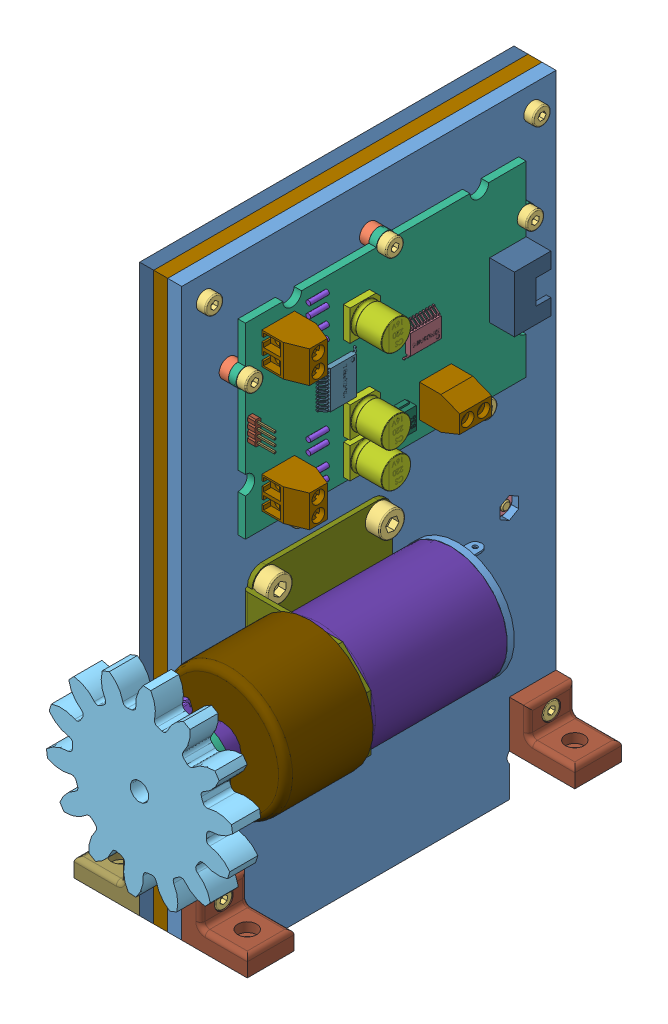
SolidWorks assembly moteur-complet, configuration Défaut. Lengths in mm.
Overall size (62.95 130 103.43).
90 component instances, 30 part files, 119 mates.
Components (placement in the parent):
- moteur-platine-1-4: moteur-platine-1 [Défaut] at (-59.9962 -68.9698 170) size (3 130 80)
- Grove button-1: Grove button [Défaut] at (-66.7015 -12.8903 110) x (0 -1 0) z (0 0 -1) size (20 11.6 23.6)
  - PCB grove 20x20-1: PCB grove 20x20 [Défaut] at (2.0795 1.2947 0) size (20 1.6 23.6)
  - 603 resistor 102-1: 603 resistor 102 [Default] at (2.0895 2.8947 -6.319) x (0 0 1) z (-1 0 0) size (2.36 0.62 1.03)
  - tactileswitch-CMS-1: tactileswitch-CMS [Default] at (-2.4169 2.8947 0.0035) x (0 0 1) z (-1 0 0) size (8.41 4.95 6.01)
  - Connecteur Grove (droit CMS)-1: Connecteur Grove (droit CMS) [Défaut] at (5.0795 2.8947 0) x (-1 0 0) z (0 1 0) size (6.5 14 10)
  - 603 resistor 102-2: 603 resistor 102 [Default] at (3.5895 2.8947 -6.319) x (0 0 1) z (-1 0 0) size (2.36 0.62 1.03)
- Grove I2C Motor driver TB6612FNG-1: Grove I2C Motor driver TB6612FNG [Défaut] at (-118.1962 28.5169 135.6463) x (0 0 1) z (1 0 0) size (64 44 12.2)
  - Plaque de base-1: Plaque de base [Défaut] at (-5.6463 -2.5133 63.2) size (64 44 1.6)
  - CS 220 16V-1: CS 220 16V [Défaut] at (0.1237 13.2167 64.8) x (1 0 0) z (0 -1 0) size (6.54 8.01 6.54)
  - CS 220 16V-2: CS 220 16V [Défaut] at (0.1237 5.6767 64.8) x (1 0 0) z (0 -1 0) size (6.54 8.01 6.54)
  - CS 220 16V-3: CS 220 16V [Défaut] at (0.1237 -12.2433 64.8) x (1 0 0) z (0 -1 0) size (6.54 8.01 6.54)
  - D1-1: D1 [Défaut] at (7.4081 5.2819 65.3) x (0 0.946795 -0.321836) z (1 0 0) size (1 1 4)
  - D1-2: D1 [Défaut] at (7.4081 7.7235 65.3) x (0 0.786026 0.618193) z (1 0 0) size (1 1 4)
  - D1-3: D1 [Défaut] at (7.4081 14.4025 65.3) x (0 0.953842 0.300308) z (1 0 0) size (1 1 4)
  - D1-4: D1 [Défaut] at (7.4081 11.9602 65.3) x (0 0.659384 0.751806) z (1 0 0) size (1 1 4)
  - D1-5: D1 [Défaut] at (7.4081 -17.5815 65.3) x (0 -0.999835 -0.018161) z (1 0 0) size (1 1 4)
  - D1-6: D1 [Défaut] at (7.4081 -14.133 65.3) x (0 0.806812 -0.590809) z (1 0 0) size (1 1 4)
  - D1-7: D1 [Défaut] at (7.4081 -11.4343 65.3) x (0 -0.166774 0.985995) z (1 0 0) size (1 1 4)
  - D1-8: D1 [Défaut] at (7.4081 -20.0356 65.3) x (0 0.962631 -0.270816) z (1 0 0) size (1 1 4)
  - bornier double-1: bornier double [Défaut] at (20.8537 7.1995 64.8) x (0 1 0) z (1 0 0) size (6.8 12.2 7)
  - bornier double-2: bornier double [Défaut] at (-12.8463 13.9867 64.8) x (-1 0 0) z (0 1 0) size (6.8 12.2 7)
  - bornier double-3: bornier double [Défaut] at (20.8537 -19.5133 64.8) x (0 1 0) z (1 0 0) size (6.8 12.2 7)
  - Grove Connecteur-1: Grove Connecteur [Défaut] at (-37.0963 -2.5133 64.05) x (1 0 0) z (0 -1 0) size (7.8 5.3 12)
  - Bloc 4 pins male-1: Bloc 4 pins male [Défaut] at (23.2493 -0.7812 63.276) x (0 -1 0) z (0 0 1) size (5.08 1.27 7.62)
    - Pin_cmi2c_Base-1: Pin_cmi2c_Base [Défaut] at (-0.1729 -0.0306 1.524) size (1.27 1.27 1.52)
    - Pin_cmi2c-1: Pin_cmi2c [Défaut] at (-0.1729 0.1472 -0.762) x (1 0 0) z (0 -1 0) size (0.36 7.62 0.36)
    - Pin_cmi2c-2: Pin_cmi2c [Défaut] at (1.0971 0.1472 -0.762) x (1 0 0) z (0 -1 0) size (0.36 7.62 0.36)
    - Pin_cmi2c-3: Pin_cmi2c [Défaut] at (2.3671 0.1472 -0.762) x (1 0 0) z (0 -1 0) size (0.36 7.62 0.36)
    - Pin_cmi2c-4: Pin_cmi2c [Défaut] at (3.6371 0.1472 -0.762) x (1 0 0) z (0 -1 0) size (0.36 7.62 0.36)
    - Pin_cmi2c_Base-2: Pin_cmi2c_Base [Défaut] at (1.0971 -0.0306 1.524) size (1.27 1.27 1.52)
    - Pin_cmi2c_Base-3: Pin_cmi2c_Base [Défaut] at (2.3671 -0.0306 1.524) size (1.27 1.27 1.52)
    - Pin_cmi2c_Base-4: Pin_cmi2c_Base [Défaut] at (3.6371 -0.0306 1.524) size (1.27 1.27 1.52)
  - Microcontroller 32F030F4P6-1: Microcontroller 32F030F4P6 [Défaut] at (-12.4961 -2.5519 65.5199) size (6.61 6.93 1.72)
  - Microcontroller TB6612FNG-1: Microcontroller TB6612FNG [Défaut] at (5.1421 -2.7086 65.5199) x (0 1 0) z (0 0 1) size (8 8.26 1.72)
  - PK13-1: PK13 [Défaut] at (-8.5328 11.2953 64.8) x (0 -1 0) z (-1 0 0) size (5.33 2 3.32)
- moteur MFA-1: moteur MFA [Défaut] at (-44.4916 -13.5198 141.6132) x (0 0 -1) z (0 -1 0) size (69.13 27.9 30)
  - moteur-support-1: moteur-support [Défaut] at (-14.3868 -12.5047 0) size (31 26.4 30)
  - moteur-corps-1: moteur-corps [Défaut] at (14.8132 1.8953 0) x (0 0 1) z (-1 0 0) size (24 24 62.63)
  - moteur-capuchon-1: moteur-capuchon [Défaut] at (-15.3868 1.8953 0) x (0 0 1) z (-1 0 0) size (27 27 18.7)
  - moteur-arriere-1: moteur-arriere [Défaut] at (16.3132 1.8953 0) x (0 0 1) z (-1 0 0) size (24 24 6.5)
- entretoise-grove-1: entretoise-grove [Défaut] at (-54.9962 51.0302 130) x (0 0.271539 0.962428) z (-1 0 0) size (4 4 2)
- entretoise-grove-2: entretoise-grove [Défaut] at (-54.9962 41.0302 100) x (0 0.358036 0.933708) z (-1 0 0) size (4 4 2)
- entretoise-grove-3: entretoise-grove [Défaut] at (-54.9962 41.0302 160) x (0 -0.42455 0.905404) z (-1 0 0) size (4 4 2)
- entretoise-grove-4: entretoise-grove [Défaut] at (-54.9962 11.0302 150) x (0 0 1) z (-1 0 0) size (4 4 2)
- entretoise-grove-5: entretoise-grove [Défaut] at (-54.9962 11.0302 110) x (0 0.014886 0.999889) z (-1 0 0) size (4 4 2)
- entretoise-grove-6: entretoise-grove [Défaut] at (-67.9962 -14.9698 120) x (0 0.014606 -0.999893) z (1 0 0) size (4 4 2)
- entretoise-grove-7: entretoise-grove [Défaut] at (-67.9962 -14.9698 100) x (0 0.432952 0.901417) z (1 0 0) size (4 4 2)
- vis-chc-1: vis-chc [Vis CHC M2x12] at (-69.5962 -14.9698 100) x (0 0.697993 -0.716105) z (0 0.716105 0.697993) size (3.8 14 3.8)
- vis-chc-2: vis-chc [Vis CHC M2x12] at (-69.5962 -14.9698 120) x (0 0.185382 -0.982666) z (0 0.982666 0.185382) size (3.8 14 3.8)
- vis-chc-3: vis-chc [Vis CHC M2x12] at (-53.3962 41.0302 100) x (0 0.381849 -0.924225) z (0 -0.924225 -0.381849) size (3.8 14 3.8)
- vis-chc-4: vis-chc [Vis CHC M2x12] at (-53.3962 51.0302 130) x (0 0.381849 -0.924225) z (0 -0.924225 -0.381849) size (3.8 14 3.8)
- vis-chc-5: vis-chc [Vis CHC M2x12] at (-53.3962 41.0302 160) x (0 0.381849 -0.924225) z (0 -0.924225 -0.381849) size (3.8 14 3.8)
- vis-chc-6: vis-chc [Vis CHC M2x12] at (-53.3962 11.0302 150) x (0 0.381849 -0.924225) z (0 -0.924225 -0.381849) size (3.8 14 3.8)
- vis-chc-7: vis-chc [Vis CHC M2x12] at (-53.3962 11.0302 110) x (0 0.381849 -0.924225) z (0 -0.924225 -0.381849) size (3.8 14 3.8)
- ecrou-h-2: ecrou-h [6007 HU M2] at (-59.9962 -14.9698 120) x (0 0.866025 0.5) z (0 -0.5 0.866025) size (4 1.6 4.62)
- ecrou-h-3: ecrou-h [6007 HU M2] at (-59.9962 -14.9698 100) x (0 0 1) z (0 -1 0) size (4 1.6 4.62)
- ecrou-h-4: ecrou-h [6007 HU M2] at (-64.5962 11.0302 110) x (0 0.866025 0.5) z (0 -0.5 0.866025) size (4 1.6 4.62)
- ecrou-h-5: ecrou-h [6007 HU M2] at (-64.5962 11.0302 150) x (0 0.866025 0.5) z (0 -0.5 0.866025) size (4 1.6 4.62)
- ecrou-h-6: ecrou-h [6007 HU M2] at (-64.5962 41.0302 160) x (0 0.866025 0.5) z (0 -0.5 0.866025) size (4 1.6 4.62)
- ecrou-h-7: ecrou-h [6007 HU M2] at (-64.5962 51.0302 130) x (0 0.866025 0.5) z (0 -0.5 0.866025) size (4 1.6 4.62)
- ecrou-h-8: ecrou-h [6007 HU M2] at (-64.5962 41.0302 100) x (0 0.866025 0.5) z (0 -0.5 0.866025) size (4 1.6 4.62)
- vis-chc-8: vis-chc [Vis CHC M3x10] at (-55.9962 -1.5198 129) x (0 0.773717 -0.633531) z (0 -0.633531 -0.773717) size (5.5 13 5.5)
- vis-chc-9: vis-chc [Vis CHC M3x10] at (-55.9962 -1.5198 153) x (0 0.483049 -0.875594) z (0 -0.875594 -0.483049) size (5.5 13 5.5)
- vis-chc-10: vis-chc [Vis CHC M3x10] at (-55.9962 -25.5198 153) x (0 0.381849 -0.924225) z (0 -0.924225 -0.381849) size (5.5 13 5.5)
- vis-chc-11: vis-chc [Vis CHC M3x10] at (-55.9962 -25.5198 129) x (0 0.381849 -0.924225) z (0 -0.924225 -0.381849) size (5.5 13 5.5)
- ecrou-h-9: ecrou-h [6012 HU M3] at (-65.3962 -1.5198 153) x (0 0.866025 0.5) z (0 -0.5 0.866025) size (5.5 2.4 6.35)
- ecrou-h-10: ecrou-h [6012 HU M3] at (-65.3962 -25.5198 153) x (0 0.866025 0.5) z (0 -0.5 0.866025) size (5.5 2.4 6.35)
- ecrou-h-11: ecrou-h [6012 HU M3] at (-65.3962 -25.5198 129) x (0 0.866025 -0.5) z (0 0.5 0.866025) size (5.5 2.4 6.35)
- ecrou-h-12: ecrou-h [6012 HU M3] at (-65.3962 -1.5198 129) x (0 0.866025 -0.5) z (0 0.5 0.866025) size (5.5 2.4 6.35)
- vis-chc-12: vis-chc [Vis CHC M2x12] at (-56.9962 56.0302 165) x (0 0.381849 -0.924225) z (0 -0.924225 -0.381849) size (3.8 14 3.8)
- vis-chc-13: vis-chc [Vis CHC M2x12] at (-56.9962 56.0302 95) x (0 -0.857895 -0.513826) z (0 -0.513826 0.857895) size (3.8 14 3.8)
- vis-chc-14: vis-chc [Vis CHC M2x16] at (-54.9962 -52.9698 95) x (0 -0.431797 -0.901971) z (0 -0.901971 0.431797) size (3.8 18 3.8)
- vis-chc-15: vis-chc [Vis CHC M2x16] at (-54.9962 -52.9698 165) x (0 0.381849 -0.924225) z (0 -0.924225 -0.381849) size (3.8 18 3.8)
- ecrou-h-13: ecrou-h [6007 HU M2] at (-67.5962 56.0302 165) x (0 0.866025 0.5) z (0 -0.5 0.866025) size (4 1.6 4.62)
- ecrou-h-14: ecrou-h [6007 HU M2] at (-67.5962 56.0302 95) x (0 0.866025 0.5) z (0 -0.5 0.866025) size (4 1.6 4.62)
- ecrou-h-15: ecrou-h [6007 HU M2] at (-69.5962 -52.9698 165) x (0 1 0) z (0 0 1) size (4 1.6 4.62)
- ecrou-h-16: ecrou-h [6007 HU M2] at (-69.5962 -52.9698 95) x (0 0.5 0.866025) z (0 -0.866025 0.5) size (4 1.6 4.62)
- engrenage-complet-1: engrenage-complet [Défaut] at (-42.1676 -13.7474 193.43) x (0.932852 0.36026 0) z (0 0 -1) size (39.32 40 14.36)
  - engrenage-1: engrenage [Défaut] at (1.0609 0.1936 0) size (39.32 40 6)
  - engrenage-bague_arret-1: engrenage-bague_arret [Défaut] at (-0.3178 -0.3667 13.5) x (-1 0 0) z (0 0 -1) size (24 24 8)
  - vis-tc-m3x6.5-1: vis-tc-m3x6.5 [Défaut] at (8.6822 -0.3667 1.1) x (1 0 0) z (0 -1 0) size (5.6 8.09 5.6)
  - vis-tc-m3x6.5-2: vis-tc-m3x6.5 [Défaut] at (-9.3178 -0.3667 1.1) x (1 0 0) z (0 -1 0) size (5.6 8.09 5.6)
  - vis-tc-m3x6-1: vis-tc-m3x6 [Défaut] at (-0.3178 -8.4167 10.5) x (-0.611546 0 0.791209) z (0.791209 0 0.611546) size (5.5 7.83 5.5)
- moteur-platine-2-5: moteur-platine-2 [Défaut] at (-62.9962 -68.9698 170) size (3 130 80)
- moteur-platine-3-3: moteur-platine-3 [Défaut] at (-65.9962 -68.9698 170) size (3 130 80)
- equerre-1: equerre [Défaut] at (-56.9962 -59.9698 165) x (0 0 -1) z (1 0 0) size (10 10 14)
- equerre-2: equerre [Défaut] at (-56.9962 -59.9698 95) x (0 0 -1) z (1 0 0) size (10 10 14)
- equerre-ecrou-1: equerre-ecrou [Défaut] at (-65.9962 -59.9698 95) x (0 0 1) z (-1 0 0) size (10 10 14)
- equerre-ecrou-2: equerre-ecrou [Défaut] at (-65.9962 -59.9698 165) x (0 0 1) z (-1 0 0) size (10 10 14)
Mates (geometry in assembly coordinates):
- Coïncidente1: coincident anti-aligned: plane of moteur-platine-1 through (-56.9962 -61.1012 161.1314) normal (1 0 0); plane of moteur MFA-1/moteur-support-1 through (-56.9962 -25.5198 153) normal (-1 0 0)
- Coaxiale1: concentric anti-aligned: cylinder of moteur-platine-1 through (-59.9962 -1.5198 129) axis (1 0 0) radius 1.5; cylinder of moteur MFA-1/moteur-support-1 through (-30.5962 -1.5198 129) axis (-1 0 0) radius 1.65
- Coaxiale2: concentric anti-aligned: cylinder of moteur-platine-1 through (-59.9962 -25.5198 129) axis (1 0 0) radius 1.5; cylinder of moteur MFA-1/moteur-support-1 through (-30.5962 -25.5198 129) axis (-1 0 0) radius 1.65
- Parallèle1: parallel aligned: plane of moteur-platine-1 through (-56.9962 61.0302 90) normal (0 0 -1); plane of Grove I2C Motor driver TB6612FNG-1/Plaque de base-1 through (-53.3962 11.0302 100) normal (0 0 -1)
- Parallèle2: parallel aligned: plane of moteur-platine-1 through (-56.9962 61.0302 170) normal (0 1 0); plane of Grove I2C Motor driver TB6612FNG-1/Plaque de base-1 through (-53.3962 51.0302 132) normal (0 1 0)
- Coaxiale3: concentric anti-aligned: cylinder of Grove I2C Motor driver TB6612FNG-1/Plaque de base-1 through (-53.3962 11.0302 110) axis (-1 0 0) radius 1; cylinder of entretoise-grove-5 through (-56.9962 11.0302 110) axis (1 0 0) radius 1
- Coïncidente4: coincident anti-aligned: plane of Grove I2C Motor driver TB6612FNG-1/Plaque de base-1 through (-54.9962 21.0302 100) normal (-1 0 0); plane of entretoise-grove-5 through (-54.9962 11.0302 110) normal (1 0 0)
- Coaxiale4: concentric anti-aligned: cylinder of Grove I2C Motor driver TB6612FNG-1/Plaque de base-1 through (-53.3962 11.0302 150) axis (-1 0 0) radius 1; cylinder of entretoise-grove-4 through (-56.9962 11.0302 150) axis (1 0 0) radius 1
- Coïncidente5: coincident anti-aligned: plane of Grove I2C Motor driver TB6612FNG-1/Plaque de base-1 through (-54.9962 21.0302 100) normal (-1 0 0); plane of entretoise-grove-4 through (-54.9962 11.0302 150) normal (1 0 0)
- Coaxiale5: concentric anti-aligned: cylinder of Grove I2C Motor driver TB6612FNG-1/Plaque de base-1 through (-53.3962 41.0302 100) axis (-1 0 0) radius 1; cylinder of entretoise-grove-2 through (-56.9962 41.0302 100) axis (1 0 0) radius 1
- Coïncidente6: coincident anti-aligned: plane of Grove I2C Motor driver TB6612FNG-1/Plaque de base-1 through (-54.9962 21.0302 100) normal (-1 0 0); plane of entretoise-grove-2 through (-54.9962 41.0302 100) normal (1 0 0)
- Coaxiale6: concentric anti-aligned: cylinder of Grove I2C Motor driver TB6612FNG-1/Plaque de base-1 through (-53.3962 41.0302 160) axis (-1 0 0) radius 1; cylinder of entretoise-grove-3 through (-56.9962 41.0302 160) axis (1 0 0) radius 1
- Coïncidente7: coincident anti-aligned: plane of Grove I2C Motor driver TB6612FNG-1/Plaque de base-1 through (-54.9962 21.0302 100) normal (-1 0 0); plane of entretoise-grove-3 through (-54.9962 41.0302 160) normal (1 0 0)
- Coaxiale7: concentric anti-aligned: cylinder of Grove I2C Motor driver TB6612FNG-1/Plaque de base-1 through (-53.3962 51.0302 130) axis (-1 0 0) radius 1; cylinder of entretoise-grove-1 through (-56.9962 51.0302 130) axis (1 0 0) radius 1
- Coïncidente8: coincident anti-aligned: plane of Grove I2C Motor driver TB6612FNG-1/Plaque de base-1 through (-54.9962 21.0302 100) normal (-1 0 0); plane of entretoise-grove-1 through (-54.9962 51.0302 130) normal (1 0 0)
- Coïncidente9: coincident anti-aligned: plane of moteur-platine-1 through (-56.9962 -61.1012 161.1314) normal (1 0 0); plane of entretoise-grove-3 through (-56.9962 41.0302 160) normal (-1 0 0)
- Coaxiale8: concentric aligned: cylinder of moteur-platine-1 through (-59.9962 11.0302 150) axis (1 0 0) radius 1; cylinder of entretoise-grove-4 through (-56.9962 11.0302 150) axis (1 0 0) radius 1
- Coaxiale9: concentric anti-aligned: cylinder of Grove button-1/PCB grove 20x20-1 through (-69.5962 -14.9698 120) axis (1 0 0) radius 1.1; cylinder of entretoise-grove-6 through (-65.9962 -14.9698 120) axis (-1 0 0) radius 1
- Coaxiale10: concentric anti-aligned: cylinder of Grove button-1/PCB grove 20x20-1 through (-69.5962 -14.9698 100) axis (1 0 0) radius 1.1; cylinder of entretoise-grove-7 through (-65.9962 -14.9698 100) axis (-1 0 0) radius 1
- Coïncidente11: coincident anti-aligned: plane of Grove button-1/PCB grove 20x20-1 through (-67.9962 -14.9698 110) normal (1 0 0); plane of entretoise-grove-7 through (-67.9962 -14.9698 100) normal (-1 0 0)
- Coaxiale13: concentric anti-aligned: cylinder of moteur MFA-1/moteur-corps-1 through (-42.5962 -13.5198 189.43) axis (0 0 -1) radius 2; cylinder of engrenage-complet-1/engrenage-bague_arret-1 through (-42.5962 -13.5198 179.93) axis (0 0 1) radius 2.05
- Distance1: distance = 0.5 mm anti-aligned: plane of engrenage-complet-1/engrenage-bague_arret-1 through (-42.5962 -13.5198 179.93) normal (0 0 -1); plane of moteur MFA-1/moteur-corps-1 through (-42.5962 -13.5198 179.43) normal (0 0 1)
- Coïncidente12: coincident anti-aligned: plane of moteur-platine-1 through (-59.9962 -61.1012 161.1314) normal (-1 0 0); plane of moteur-platine-2 through (-59.9962 -61.1012 161.1314) normal (1 0 0)
- Coïncidente13: coincident aligned: plane of moteur-platine-1 through (-56.9962 61.0302 170) normal (0 1 0); plane of moteur-platine-2 through (-59.9962 61.0302 170) normal (0 1 0)
- Coïncidente14: coincident aligned: plane of moteur-platine-1 through (-56.9962 61.0302 90) normal (0 0 -1); plane of moteur-platine-2 through (-59.9962 61.0302 90) normal (0 0 -1)
- Coïncidente15: coincident anti-aligned: plane of moteur-platine-2 through (-62.9962 -61.1012 161.1314) normal (-1 0 0); plane of moteur-platine-3-3 through (-62.9962 -61.1012 161.1314) normal (1 0 0)
- Coïncidente16: coincident aligned: plane of moteur-platine-2 through (-59.9962 61.0302 170) normal (0 1 0); plane of moteur-platine-3-3 through (-62.9962 61.0302 170) normal (0 1 0)
- Coïncidente17: coincident aligned: plane of moteur-platine-1 through (-56.9962 61.0302 90) normal (0 0 -1); plane of moteur-platine-3-3 through (-62.9962 61.0302 90) normal (0 0 -1)
- Coïncidente18: coincident anti-aligned: plane of entretoise-grove-7 through (-65.9962 -14.9698 100) normal (1 0 0); plane of moteur-platine-3-3 through (-65.9962 -61.1012 161.1314) normal (-1 0 0)
- Coïncidente19: coincident anti-aligned: plane of entretoise-grove-6 through (-65.9962 -14.9698 120) normal (1 0 0); plane of moteur-platine-3-3 through (-65.9962 -61.1012 161.1314) normal (-1 0 0)
- Coïncidente21: coincident anti-aligned: plane of Grove button-1/PCB grove 20x20-1 through (-69.5962 -14.9698 110) normal (-1 0 0); plane of vis-chc-2 through (-69.5962 -14.9698 120) normal (1 0 0)
- Coaxiale15: concentric aligned: cylinder of vis-chc-2 through (-57.5962 -14.9698 120) axis (-1 0 0) radius 1; cylinder of ecrou-h-2 through (-58.3962 -14.9698 120) axis (-1 0 0) radius 0.7835
- Parallèle4: parallel aligned: plane of moteur-platine-1 through (-56.9962 61.0302 90) normal (0 0 -1); plane of ecrou-h-2 through (-58.3962 -13.8151 118) normal (0 0 -1)
- Coïncidente25: coincident anti-aligned: plane of Grove button-1/PCB grove 20x20-1 through (-69.5962 -14.9698 110) normal (-1 0 0); plane of vis-chc-1 through (-69.5962 -14.9698 100) normal (1 0 0)
- Coaxiale17: concentric aligned: cylinder of vis-chc-1 through (-57.5962 -14.9698 100) axis (-1 0 0) radius 1; cylinder of ecrou-h-3 through (-58.3962 -14.9698 100) axis (-1 0 0) radius 0.7835
- Parallèle5: parallel aligned: plane of moteur-platine-1 through (-56.9962 61.0302 90) normal (0 0 -1); plane of ecrou-h-3 through (-58.3962 -13.8151 98) normal (0 0 -1)
- Coaxiale18: concentric anti-aligned: cylinder of Grove I2C Motor driver TB6612FNG-1/Plaque de base-1 through (-53.3962 11.0302 110) axis (-1 0 0) radius 1; cylinder of vis-chc-7 through (-65.3962 11.0302 110) axis (1 0 0) radius 1
- Coaxiale19: concentric anti-aligned: cylinder of Grove I2C Motor driver TB6612FNG-1/Plaque de base-1 through (-53.3962 11.0302 150) axis (-1 0 0) radius 1; cylinder of vis-chc-6 through (-65.3962 11.0302 150) axis (1 0 0) radius 1
- Coaxiale20: concentric anti-aligned: cylinder of Grove I2C Motor driver TB6612FNG-1/Plaque de base-1 through (-53.3962 41.0302 160) axis (-1 0 0) radius 1; cylinder of vis-chc-5 through (-65.3962 41.0302 160) axis (1 0 0) radius 1
- Coaxiale21: concentric anti-aligned: cylinder of Grove I2C Motor driver TB6612FNG-1/Plaque de base-1 through (-53.3962 51.0302 130) axis (-1 0 0) radius 1; cylinder of vis-chc-4 through (-65.3962 51.0302 130) axis (1 0 0) radius 1
- Coaxiale22: concentric anti-aligned: cylinder of Grove I2C Motor driver TB6612FNG-1/Plaque de base-1 through (-53.3962 41.0302 100) axis (-1 0 0) radius 1; cylinder of vis-chc-3 through (-65.3962 41.0302 100) axis (1 0 0) radius 1
- Coïncidente28: coincident anti-aligned: plane of Grove I2C Motor driver TB6612FNG-1/Plaque de base-1 through (-53.3962 21.0302 100) normal (1 0 0); plane of vis-chc-3 through (-53.3962 41.0302 100) normal (-1 0 0)
- Coïncidente29: coincident anti-aligned: plane of Grove I2C Motor driver TB6612FNG-1/Plaque de base-1 through (-53.3962 21.0302 100) normal (1 0 0); plane of vis-chc-4 through (-53.3962 51.0302 130) normal (-1 0 0)
- Coïncidente30: coincident anti-aligned: plane of Grove I2C Motor driver TB6612FNG-1/Plaque de base-1 through (-53.3962 21.0302 100) normal (1 0 0); plane of vis-chc-5 through (-53.3962 41.0302 160) normal (-1 0 0)
- Coïncidente31: coincident anti-aligned: plane of Grove I2C Motor driver TB6612FNG-1/Plaque de base-1 through (-53.3962 21.0302 100) normal (1 0 0); plane of vis-chc-6 through (-53.3962 11.0302 150) normal (-1 0 0)
- Coïncidente32: coincident anti-aligned: plane of Grove I2C Motor driver TB6612FNG-1/Plaque de base-1 through (-53.3962 21.0302 100) normal (1 0 0); plane of vis-chc-7 through (-53.3962 11.0302 110) normal (-1 0 0)
- Coaxiale23: concentric anti-aligned: cylinder of vis-chc-7 through (-65.3962 11.0302 110) axis (1 0 0) radius 1; cylinder of ecrou-h-4 through (-62.9962 11.0302 110) axis (-1 0 0) radius 0.7835
- Coaxiale24: concentric anti-aligned: cylinder of vis-chc-3 through (-65.3962 41.0302 100) axis (1 0 0) radius 1; cylinder of ecrou-h-8 through (-62.9962 41.0302 100) axis (-1 0 0) radius 0.7835
- Coaxiale25: concentric anti-aligned: cylinder of vis-chc-4 through (-65.3962 51.0302 130) axis (1 0 0) radius 1; cylinder of ecrou-h-7 through (-62.9962 51.0302 130) axis (-1 0 0) radius 0.7835
- Coaxiale26: concentric anti-aligned: cylinder of vis-chc-5 through (-65.3962 41.0302 160) axis (1 0 0) radius 1; cylinder of ecrou-h-6 through (-62.9962 41.0302 160) axis (-1 0 0) radius 0.7835
- Coaxiale27: concentric anti-aligned: cylinder of vis-chc-6 through (-65.3962 11.0302 150) axis (1 0 0) radius 1; cylinder of ecrou-h-5 through (-62.9962 11.0302 150) axis (-1 0 0) radius 0.7835
- Parallèle6: parallel aligned: plane of moteur-platine-3-3 through (-62.9962 -59.9698 170) normal (0 0 1); plane of ecrou-h-6 through (-62.9962 39.8755 162) normal (0 0 1)
- Parallèle7: parallel aligned: plane of moteur-platine-3-3 through (-62.9962 -59.9698 170) normal (0 0 1); plane of ecrou-h-7 through (-62.9962 49.8755 132) normal (0 0 1)
- Parallèle8: parallel aligned: plane of moteur-platine-3-3 through (-62.9962 -59.9698 170) normal (0 0 1); plane of ecrou-h-8 through (-62.9962 39.8755 102) normal (0 0 1)
- Parallèle9: parallel aligned: plane of moteur-platine-3-3 through (-62.9962 -59.9698 170) normal (0 0 1); plane of ecrou-h-5 through (-62.9962 9.8755 152) normal (0 0 1)
- Parallèle10: parallel aligned: plane of moteur-platine-3-3 through (-62.9962 -59.9698 170) normal (0 0 1); plane of ecrou-h-4 through (-62.9962 9.8755 112) normal (0 0 1)
- Coaxiale28: concentric anti-aligned: cylinder of moteur MFA-1/moteur-support-1 through (-30.5962 -1.5198 153) axis (-1 0 0) radius 1.65; cylinder of vis-chc-9 through (-65.9962 -1.5198 153) axis (1 0 0) radius 1.5
- Coaxiale29: concentric anti-aligned: cylinder of moteur MFA-1/moteur-support-1 through (-30.5962 -1.5198 129) axis (-1 0 0) radius 1.65; cylinder of vis-chc-8 through (-65.9962 -1.5198 129) axis (1 0 0) radius 1.5
- Coaxiale30: concentric anti-aligned: cylinder of moteur MFA-1/moteur-support-1 through (-30.5962 -25.5198 129) axis (-1 0 0) radius 1.65; cylinder of vis-chc-11 through (-65.9962 -25.5198 129) axis (1 0 0) radius 1.5
- Coaxiale31: concentric anti-aligned: cylinder of moteur MFA-1/moteur-support-1 through (-30.5962 -25.5198 153) axis (-1 0 0) radius 1.65; cylinder of vis-chc-10 through (-65.9962 -25.5198 153) axis (1 0 0) radius 1.5
- Coïncidente43: coincident anti-aligned: plane of moteur MFA-1/moteur-support-1 through (-55.9962 -29.752 156) normal (1 0 0); plane of vis-chc-11 through (-55.9962 -25.5198 129) normal (-1 0 0)
- Coïncidente44: coincident aligned: plane of moteur MFA-1/moteur-support-1 through (-55.9962 -29.752 156) normal (1 0 0); circle of vis-chc-10
- Coïncidente45: coincident anti-aligned: plane of moteur MFA-1/moteur-support-1 through (-55.9962 -29.752 156) normal (1 0 0); plane of vis-chc-8 through (-55.9962 -1.5198 129) normal (-1 0 0)
- Coïncidente46: coincident anti-aligned: plane of moteur MFA-1/moteur-support-1 through (-55.9962 -29.752 156) normal (1 0 0); plane of vis-chc-9 through (-55.9962 -1.5198 153) normal (-1 0 0)
- Coaxiale32: concentric anti-aligned: cylinder of vis-chc-8 through (-65.9962 -1.5198 129) axis (1 0 0) radius 1.5; cylinder of ecrou-h-12 through (-62.9962 -1.5198 129) axis (-1 0 0) radius 1.2295
- Coaxiale33: concentric anti-aligned: cylinder of vis-chc-10 through (-65.9962 -25.5198 153) axis (1 0 0) radius 1.5; cylinder of ecrou-h-10 through (-62.9962 -25.5198 153) axis (-1 0 0) radius 1.2295
- Coaxiale34: concentric anti-aligned: cylinder of vis-chc-9 through (-65.9962 -1.5198 153) axis (1 0 0) radius 1.5; cylinder of ecrou-h-9 through (-62.9962 -1.5198 153) axis (-1 0 0) radius 1.2295
- Coaxiale35: concentric anti-aligned: cylinder of vis-chc-11 through (-65.9962 -25.5198 129) axis (1 0 0) radius 1.5; cylinder of ecrou-h-11 through (-62.9962 -25.5198 129) axis (-1 0 0) radius 1.2295
- Parallèle11: parallel aligned: plane of moteur-platine-3-3 through (-62.9962 -59.9698 170) normal (0 0 1); plane of ecrou-h-10 through (-62.9962 -27.1075 155.75) normal (0 0 1)
- Parallèle12: parallel aligned: plane of moteur-platine-3-3 through (-62.9962 -59.9698 170) normal (0 0 1); plane of ecrou-h-11 through (-62.9962 -27.1075 131.75) normal (0 0 1)
- Parallèle13: parallel aligned: plane of moteur-platine-3-3 through (-62.9962 -59.9698 170) normal (0 0 1); plane of ecrou-h-12 through (-62.9962 -3.1075 131.75) normal (0 0 1)
- Parallèle14: parallel aligned: plane of moteur-platine-3-3 through (-62.9962 -59.9698 170) normal (0 0 1); plane of ecrou-h-9 through (-62.9962 -3.1075 155.75) normal (0 0 1)
- Coaxiale36: concentric aligned: cylinder of moteur-platine-1 through (-59.9962 56.0302 165) axis (1 0 0) radius 1; cylinder of vis-chc-12 through (-68.9962 56.0302 165) axis (1 0 0) radius 1
- Coïncidente55: coincident anti-aligned: plane of moteur-platine-1 through (-56.9962 -61.1012 161.1314) normal (1 0 0); plane of vis-chc-12 through (-56.9962 56.0302 165) normal (-1 0 0)
- Coaxiale37: concentric aligned: cylinder of moteur-platine-1 through (-59.9962 56.0302 95) axis (1 0 0) radius 1; cylinder of vis-chc-13 through (-68.9962 56.0302 95) axis (1 0 0) radius 1
- Coïncidente56: coincident anti-aligned: plane of moteur-platine-1 through (-56.9962 -61.1012 161.1314) normal (1 0 0); plane of vis-chc-13 through (-56.9962 56.0302 95) normal (-1 0 0)
- Coaxiale39: concentric anti-aligned: cylinder of vis-chc-13 through (-68.9962 56.0302 95) axis (1 0 0) radius 1; circle of ecrou-h-14
- Coïncidente57: coincident anti-aligned: plane of moteur-platine-3-3 through (-65.9962 -61.1012 161.1314) normal (-1 0 0); plane of ecrou-h-14 through (-65.9962 58.3396 95) normal (1 0 0)
- Parallèle15: parallel aligned: plane of moteur-platine-3-3 through (-62.9962 61.0302 90) normal (0 0 -1); plane of ecrou-h-14 through (-65.9962 57.1849 93) normal (0 0 -1)
- Coaxiale40: concentric anti-aligned: cylinder of vis-chc-12 through (-68.9962 56.0302 165) axis (1 0 0) radius 1; cylinder of ecrou-h-13 through (-65.9962 56.0302 165) axis (-1 0 0) radius 0.7835
- Coïncidente60: coincident anti-aligned: plane of moteur-platine-3-3 through (-65.9962 -61.1012 161.1314) normal (-1 0 0); plane of ecrou-h-13 through (-65.9962 58.3396 165) normal (1 0 0)
- Parallèle17: parallel aligned: plane of moteur-platine-3-3 through (-62.9962 -59.9698 170) normal (0 0 1); plane of ecrou-h-13 through (-65.9962 54.8755 167) normal (0 0 1)
- Coïncidente62: coincident anti-aligned: plane of moteur-platine-1 through (-56.9962 -61.1012 161.1314) normal (1 0 0); plane of equerre-2 through (-56.9962 -59.9698 95) normal (-1 0 0)
- Coaxiale41: concentric aligned: cylinder of moteur-platine-1 through (-59.9962 -52.9698 95) axis (1 0 0) radius 1; cylinder of equerre-2 through (-56.9962 -52.9698 95) axis (1 0 0) radius 1
- Coïncidente63: coincident aligned: plane of moteur-platine-1 through (-56.9962 -59.9698 97.7373) normal (0 -1 0); plane of equerre-2 through (-52.9962 -59.9698 100) normal (0 -1 0)
- Coaxiale42: concentric aligned: cylinder of moteur-platine-1 through (-59.9962 -52.9698 165) axis (1 0 0) radius 1; cylinder of equerre-1 through (-56.9962 -52.9698 165) axis (1 0 0) radius 1
- Coïncidente64: coincident aligned: plane of moteur-platine-1 through (-56.9962 -59.9698 162.2627) normal (0 -1 0); plane of equerre-1 through (-52.9962 -59.9698 170) normal (0 -1 0)
- Coïncidente65: coincident anti-aligned: plane of moteur-platine-1 through (-56.9962 -61.1012 161.1314) normal (1 0 0); plane of equerre-1 through (-56.9962 -59.9698 165) normal (-1 0 0)
- Coaxiale43: concentric aligned: cylinder of vis-chc-15 through (-70.9962 -52.9698 165) axis (1 0 0) radius 1; cylinder of equerre-1 through (-56.9962 -52.9698 165) axis (1 0 0) radius 1
- Coïncidente66: coincident anti-aligned: plane of vis-chc-15 through (-54.9962 -52.9698 165) normal (-1 0 0); plane of equerre-1 through (-54.9962 -52.9698 165) normal (1 0 0)
- Coaxiale44: concentric aligned: cylinder of vis-chc-14 through (-70.9962 -52.9698 95) axis (1 0 0) radius 1; cylinder of equerre-2 through (-56.9962 -52.9698 95) axis (1 0 0) radius 1
- Coïncidente67: coincident anti-aligned: plane of vis-chc-14 through (-54.9962 -52.9698 95) normal (-1 0 0); plane of equerre-2 through (-54.9962 -52.9698 95) normal (1 0 0)
- Coïncidente68: coincident anti-aligned: plane of moteur-platine-3-3 through (-65.9962 -61.1012 161.1314) normal (-1 0 0); plane of equerre-ecrou-2 through (-65.9962 -59.9698 165) normal (1 0 0)
- Coïncidente69: coincident anti-aligned: plane of moteur-platine-3-3 through (-65.9962 -61.1012 161.1314) normal (-1 0 0); plane of equerre-ecrou-1 through (-65.9962 -59.9698 95) normal (1 0 0)
- Coïncidente70: coincident aligned: plane of moteur-platine-3-3 through (-62.9962 -59.9698 97.7373) normal (0 -1 0); plane of equerre-ecrou-1 through (-69.9962 -59.9698 90) normal (0 -1 0)
- Coïncidente71: coincident aligned: plane of moteur-platine-3-3 through (-62.9962 -59.9698 97.7373) normal (0 -1 0); plane of equerre-ecrou-2 through (-69.9962 -59.9698 160) normal (0 -1 0)
- Coaxiale45: concentric anti-aligned: cylinder of vis-chc-14 through (-70.9962 -52.9698 95) axis (1 0 0) radius 1; cylinder of equerre-ecrou-1 through (-65.9962 -52.9698 95) axis (-1 0 0) radius 1
- Coaxiale46: concentric anti-aligned: cylinder of vis-chc-15 through (-70.9962 -52.9698 165) axis (1 0 0) radius 1; cylinder of equerre-ecrou-2 through (-65.9962 -52.9698 165) axis (-1 0 0) radius 1
- Coaxiale47: concentric anti-aligned: cylinder of vis-chc-15 through (-70.9962 -52.9698 165) axis (1 0 0) radius 1; cylinder of ecrou-h-15 through (-67.9962 -52.9698 165) axis (-1 0 0) radius 0.7835
- Parallèle18: parallel anti-aligned: plane of ecrou-h-15 through (-67.9962 -50.9698 166.1547) normal (0 1 0); plane of equerre-ecrou-2 through (-67.9962 -50.952 166.165) normal (0 -1 0)
- Coïncidente73: coincident anti-aligned: plane of ecrou-h-15 through (-67.9962 -50.9698 163.8453) normal (1 0 0); plane of equerre-ecrou-2 through (-67.9962 -59.9698 165) normal (-1 0 0)
- Coaxiale49: concentric anti-aligned: cylinder of vis-chc-14 through (-70.9962 -52.9698 95) axis (1 0 0) radius 1; cylinder of ecrou-h-16 through (-67.9962 -52.9698 95) axis (-1 0 0) radius 0.7835
- Parallèle19: parallel anti-aligned: plane of ecrou-h-16 through (-67.9962 -50.9698 96.1547) normal (0 1 0); plane of equerre-ecrou-1 through (-67.9962 -50.952 96.165) normal (0 -1 0)
- Coïncidente75: coincident anti-aligned: plane of ecrou-h-16 through (-67.9962 -50.9698 96.1547) normal (1 0 0); plane of equerre-ecrou-1 through (-67.9962 -59.9698 95) normal (-1 0 0)
- Coïncidente76: coincident anti-aligned: plane of ecrou-h-6 through (-62.9962 43.3396 160) normal (1 0 0); plane of moteur-platine-5 through (-62.9962 -61.1012 161.1314) normal (-1 0 0)
- Coïncidente77: coincident anti-aligned: plane of ecrou-h-5 through (-62.9962 13.3396 150) normal (1 0 0); plane of moteur-platine-5 through (-62.9962 -61.1012 161.1314) normal (-1 0 0)
- Coïncidente78: coincident anti-aligned: plane of ecrou-h-4 through (-62.9962 13.3396 110) normal (1 0 0); plane of moteur-platine-5 through (-62.9962 -61.1012 161.1314) normal (-1 0 0)
- Coïncidente79: coincident anti-aligned: plane of ecrou-h-8 through (-62.9962 43.3396 100) normal (1 0 0); plane of moteur-platine-5 through (-62.9962 -61.1012 161.1314) normal (-1 0 0)
- Coïncidente80: coincident anti-aligned: plane of ecrou-h-7 through (-62.9962 53.3396 130) normal (1 0 0); plane of moteur-platine-5 through (-62.9962 -61.1012 161.1314) normal (-1 0 0)
- Coïncidente81: coincident anti-aligned: plane of ecrou-h-12 through (-62.9962 0.0679 126.25) normal (1 0 0); plane of moteur-platine-5 through (-62.9962 -61.1012 161.1314) normal (-1 0 0)
- Coïncidente82: coincident anti-aligned: plane of ecrou-h-11 through (-62.9962 -23.9321 126.25) normal (1 0 0); plane of moteur-platine-5 through (-62.9962 -61.1012 161.1314) normal (-1 0 0)
- Coïncidente83: coincident anti-aligned: plane of ecrou-h-10 through (-62.9962 -22.3444 153) normal (1 0 0); plane of moteur-platine-5 through (-62.9962 -61.1012 161.1314) normal (-1 0 0)
- Coïncidente84: coincident anti-aligned: plane of ecrou-h-9 through (-62.9962 1.6556 153) normal (1 0 0); plane of moteur-platine-5 through (-62.9962 -61.1012 161.1314) normal (-1 0 0)
- Coaxiale50: concentric anti-aligned: cylinder of vis-chc-2 through (-57.5962 -14.9698 120) axis (-1 0 0) radius 1; cylinder of moteur-platine-3-3 through (-65.9962 -14.9698 120) axis (1 0 0) radius 1
- Coaxiale51: concentric anti-aligned: cylinder of vis-chc-1 through (-57.5962 -14.9698 100) axis (-1 0 0) radius 1; cylinder of moteur-platine-3-3 through (-65.9962 -14.9698 100) axis (1 0 0) radius 1
- Coïncidente85: coincident anti-aligned: plane of ecrou-h-3 through (-59.9962 -13.8151 102) normal (-1 0 0); plane of moteur-platine-2-5 through (-59.9962 -61.1012 161.1314) normal (1 0 0)
- Coïncidente86: coincident anti-aligned: plane of ecrou-h-2 through (-59.9962 -12.6604 120) normal (-1 0 0); plane of moteur-platine-2-5 through (-59.9962 -61.1012 161.1314) normal (1 0 0)
- Coaxiale52: concentric anti-aligned: cylinder of Grove button-1/PCB grove 20x20-1 through (-69.5962 -14.9698 100) axis (1 0 0) radius 1.1; cylinder of vis-chc-1 through (-57.5962 -14.9698 100) axis (-1 0 0) radius 1
- Coaxiale53: concentric anti-aligned: cylinder of Grove button-1/PCB grove 20x20-1 through (-69.5962 -14.9698 120) axis (1 0 0) radius 1.1; cylinder of vis-chc-2 through (-57.5962 -14.9698 120) axis (-1 0 0) radius 1
